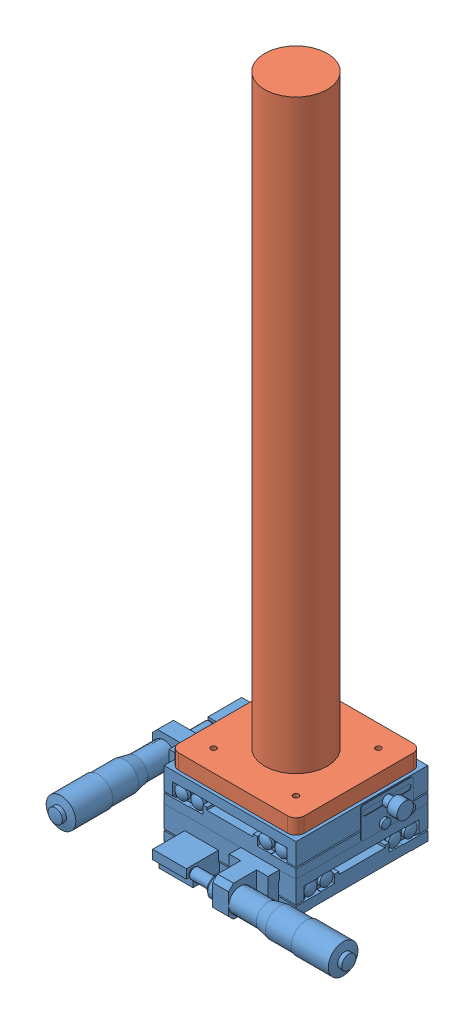
SolidWorks assembly z shaft assembled, configuration Default. Lengths in mm.
Overall size (155.6 404.54 140.9).
3 component instances, 2 part files, 6 mates.
Components (placement in the parent):
- B11-80CZ.step-1: B11-80CZ.step [Default] at (24.4701 -2.1391 -38.5314) x (1 0 0) z (0 1 0) size (130.2 117.3 20)
- B11-80CZ.step-2: B11-80CZ.step [Default] at (24.4701 17.6609 -38.5314) x (0 0 1) z (0 1 0) size (130.2 117.3 20)
- z shaft-1: z shaft [Default] at (-13.6299 37.6609 -0.4314) size (76.2 364.74 76.2)
Mates (geometry in assembly coordinates):
- Concentric1: concentric: cylinder of B11-80CZ.step-1 through (59.4701 10.8609 -73.5314) axis (0 -1 0) radius 1.65; cylinder of B11-80CZ.step-2 through (59.4701 42.6542 -73.5314) axis (0 -1 0) radius 2.25
- Concentric2: concentric: cylinder of B11-80CZ.step-1 through (-10.5299 10.8609 -73.5314) axis (0 -1 0) radius 1.65; cylinder of B11-80CZ.step-2 through (-10.5299 15.4109 -73.5314) axis (0 -1 0) radius 2.25
- Coincident1: coincident: plane of B11-80CZ.step-1 through (24.4701 17.8609 -38.5314) normal (0 1 0); plane of B11-80CZ.step-2 through (-5.5299 17.8609 -135.8702) normal (0 -1 0)
- Concentric3: concentric anti-aligned: cylinder of B11-80CZ.step-2 through (49.4701 30.6609 -63.5314) axis (0 -1 0) radius 1.65; cylinder of z shaft-1 through (49.4701 37.6609 -63.5314) axis (0 1 0) radius 1.65
- Concentric4: concentric anti-aligned: cylinder of B11-80CZ.step-2 through (-0.5299 30.6609 -63.5314) axis (0 -1 0) radius 1.65; cylinder of z shaft-1 through (-0.5299 37.6609 -63.5314) axis (0 1 0) radius 1.65
- Coincident2: coincident anti-aligned: plane of B11-80CZ.step-2 through (24.4701 37.6609 -38.5314) normal (0 1 0); plane of z shaft-1 through (-13.6299 37.6609 -0.4314) normal (0 -1 0)
